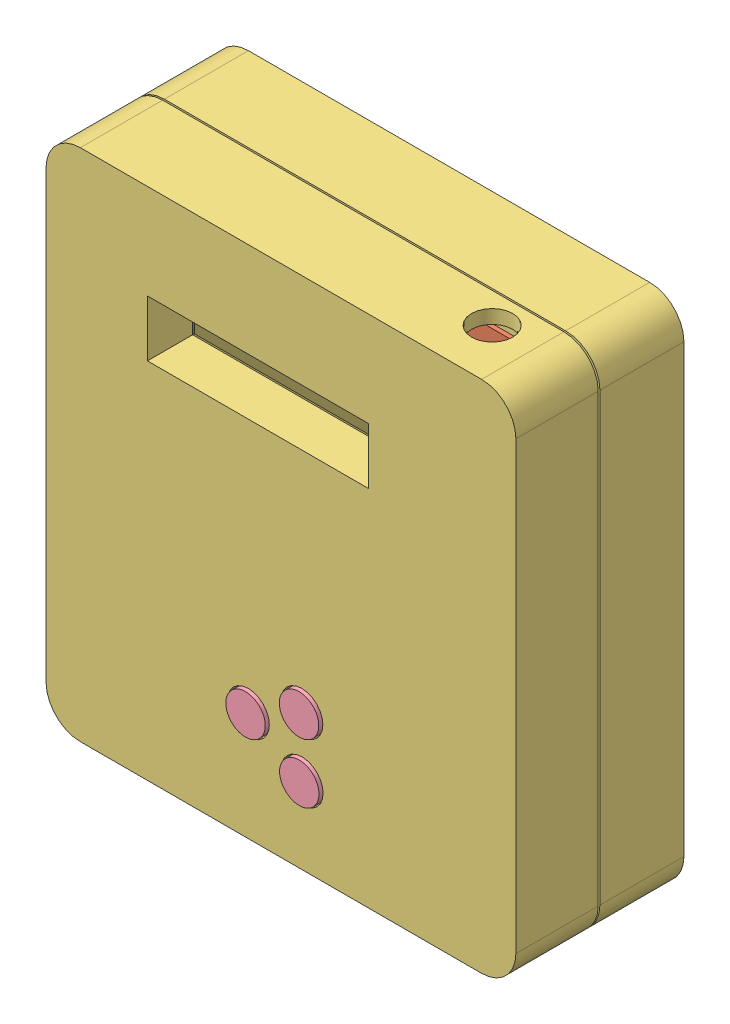
SolidWorks assembly Handheld Terminal, configuration Default. Lengths in mm.
Overall size (137 150 49.83).
106 component instances, 23 part files, 18 mates.
Components (placement in the parent):
- Handheld Terminal Circuit-1: Handheld Terminal Circuit [Default] at origin size (116.81 129.48 28.62)
  - Handheld Terminal Circuit.STEP-1: Handheld Terminal Circuit.STEP [Default] at origin size (116.81 129.48 28.62)
    - X1.STEP-1: X1.STEP [Default] at (-24.8494 -12.1588 0.625) x (0 1 0) z (0 0 1) size (11 4.5 15.2)
      - Open CASCADE STEP translator 6.8 2.2.1.STEP-1: Open CASCADE STEP translator 6.8 2.2.1.STEP [Default] at origin size (11 4.5 15.2)
        - Body_1.STEP-1: Body_1.STEP [Default] at (2.5 0 0) x (1 0 0) z (0 -1 0) size (11 15.2 4.5)
    - J1.STEP-1: J1.STEP [Default] at (27.8456 -53.6484 0.625) x (-1 0 0) z (0 0 1) size (10.16 10.16 8.71)
      - Open CASCADE STEP translator 6.8 2.3.1.STEP-1: Open CASCADE STEP translator 6.8 2.3.1.STEP [Default] at origin size (10.16 10.16 8.71)
        - Body_1-0.STEP-1: Body_1-0.STEP [Default] at origin size (10.16 10.16 3)
        - Pin_1.STEP-1: Pin_1.STEP [Default] x (0 -1 0) z (0 0 1) size (1.42 1.42 7.92)
        - Pin_2.STEP-1: Pin_2.STEP [Default] at (5.08 5.08 0) x (0 -1 0) z (0 0 1) size (1.42 1.42 7.92)
    - U2.STEP-1: U2.STEP [Default] at (37.1858 -34.3162 -0.625) x (0 -1 0) z (0 0 -1) size (3.55 6.6 1.62)
      - Open CASCADE STEP translator 6.8 2.4.1.STEP-1: Open CASCADE STEP translator 6.8 2.4.1.STEP [Default] at origin size (3.55 6.6 1.62)
        - Body_1-1.STEP-1: Body_1-1.STEP [Default] at origin size (3.55 6.6 1.62)
    - R1.STEP-1: R1.STEP [Default] at (-50.4294 44.6446 0.625) x (0 -1 0) z (0 0 1) size (10.82 1.37 5.33)
      - Open CASCADE STEP translator 6.8 2.5.1.STEP-1: Open CASCADE STEP translator 6.8 2.5.1.STEP [Default] at origin size (10.82 1.37 5.33)
        - Body_1-2.STEP-1: Body_1-2.STEP [Default] at origin size (5.08 1.37 1.37)
        - Pin_1-3.STEP-1: Pin_1-3.STEP [Default] at origin size (3.2 0.66 4.98)
        - Pin_2-4.STEP-1: Pin_2-4.STEP [Default] at (20.32 0 0) x (-1 0 0) z (0 0 1) size (3.2 0.66 4.98)
    - R2.STEP-1: R2.STEP [Default] at (-20.066 15.8496 0.625) size (10.82 1.37 5.33)
      - Open CASCADE STEP translator 6.8 2.5.1.STEP-1: Open CASCADE STEP translator 6.8 2.5.1.STEP [Default] at origin size (10.82 1.37 5.33)
        - Body_1-2.STEP-1: Body_1-2.STEP [Default] at origin size (5.08 1.37 1.37)
        - Pin_1-3.STEP-1: Pin_1-3.STEP [Default] at origin size (3.2 0.66 4.98)
        - Pin_2-4.STEP-1: Pin_2-4.STEP [Default] at (20.32 0 0) x (-1 0 0) z (0 0 1) size (3.2 0.66 4.98)
    - R3.STEP-1: R3.STEP [Default] at (-19.1008 -43.1546 0.625) x (-1 0 0) z (0 0 1) size (10.82 1.37 5.33)
      - Open CASCADE STEP translator 6.8 2.5.1.STEP-1: Open CASCADE STEP translator 6.8 2.5.1.STEP [Default] at origin size (10.82 1.37 5.33)
        - Body_1-2.STEP-1: Body_1-2.STEP [Default] at origin size (5.08 1.37 1.37)
        - Pin_1-3.STEP-1: Pin_1-3.STEP [Default] at origin size (3.2 0.66 4.98)
        - Pin_2-4.STEP-1: Pin_2-4.STEP [Default] at (20.32 0 0) x (-1 0 0) z (0 0 1) size (3.2 0.66 4.98)
    - R4.STEP-1: R4.STEP [Default] at (-19.1008 -39.751 0.625) x (-1 0 0) z (0 0 1) size (10.82 1.37 5.33)
      - Open CASCADE STEP translator 6.8 2.5.1.STEP-1: Open CASCADE STEP translator 6.8 2.5.1.STEP [Default] at origin size (10.82 1.37 5.33)
        - Body_1-2.STEP-1: Body_1-2.STEP [Default] at origin size (5.08 1.37 1.37)
        - Pin_1-3.STEP-1: Pin_1-3.STEP [Default] at origin size (3.2 0.66 4.98)
        - Pin_2-4.STEP-1: Pin_2-4.STEP [Default] at (20.32 0 0) x (-1 0 0) z (0 0 1) size (3.2 0.66 4.98)
    - R5.STEP-1: R5.STEP [Default] at (-19.2024 -46.2788 0.625) x (-1 0 0) z (0 0 1) size (10.82 1.37 5.33)
      - Open CASCADE STEP translator 6.8 2.5.1.STEP-1: Open CASCADE STEP translator 6.8 2.5.1.STEP [Default] at origin size (10.82 1.37 5.33)
        - Body_1-2.STEP-1: Body_1-2.STEP [Default] at origin size (5.08 1.37 1.37)
        - Pin_1-3.STEP-1: Pin_1-3.STEP [Default] at origin size (3.2 0.66 4.98)
        - Pin_2-4.STEP-1: Pin_2-4.STEP [Default] at (20.32 0 0) x (-1 0 0) z (0 0 1) size (3.2 0.66 4.98)
    - C1.STEP-1: C1.STEP [Default] at (-36.1294 -7.2788 0.625) size (8 2 13.25)
      - Open CASCADE STEP translator 6.8 2.10.1.STEP-1: Open CASCADE STEP translator 6.8 2.10.1.STEP [Default] at origin size (8 2 13.25)
        - Body_1-5.STEP-1: Body_1-5.STEP [Default] at (2.54 -2.54 0) x (0 1 0) z (0 0 1) size (2 8 8)
        - Pin_1-6.STEP-1: Pin_1-6.STEP [Default] x (0 -1 0) z (0 0 1) size (0.5 0.5 9.5)
        - Pin_2-7.STEP-1: Pin_2-7.STEP [Default] at (5.08 5.08 0) x (0 -1 0) z (0 0 1) size (0.5 0.5 9.5)
    - C2.STEP-1: C2.STEP [Default] at (-36.1494 -11.6788 0.625) size (8 2 13.25)
      - Open CASCADE STEP translator 6.8 2.10.1.STEP-1: Open CASCADE STEP translator 6.8 2.10.1.STEP [Default] at origin size (8 2 13.25)
        - Body_1-5.STEP-1: Body_1-5.STEP [Default] at (2.54 -2.54 0) x (0 1 0) z (0 0 1) size (2 8 8)
        - Pin_1-6.STEP-1: Pin_1-6.STEP [Default] x (0 -1 0) z (0 0 1) size (0.5 0.5 9.5)
        - Pin_2-7.STEP-1: Pin_2-7.STEP [Default] at (5.08 5.08 0) x (0 -1 0) z (0 0 1) size (0.5 0.5 9.5)
    - LCD1.STEP-1: LCD1.STEP [Default] at (-19.686 56.143 0.625) size (80 36 10.2)
      - Open CASCADE STEP translator 6.8 2.12.1.STEP-1: Open CASCADE STEP translator 6.8 2.12.1.STEP [Default] at origin size (80 36 10.2)
        - Body_1-8.STEP-1: Body_1-8.STEP [Default] at (13 -17 0) x (1 0 0) z (0 -1 0) size (80 10.2 36)
    - SW1.STEP-1: SW1.STEP [Default] at (-7.2644 -37.4396 0.625) x (0 -1 0) z (0 0 1) size (12.01 10.01 12.01)
      - Open CASCADE STEP translator 6.8 2.13.1.STEP-1: Open CASCADE STEP translator 6.8 2.13.1.STEP [Default] at origin size (12.01 10.01 12.01)
        - Body_1-9.STEP-1: Body_1-9.STEP [Default] at (6 -2 0) x (1 0 0) z (0 -1 0) size (12.01 10.01 12.01)
    - SW2.STEP-1: SW2.STEP [Default] at (8.3378 -29.1306 0.625) x (0 -1 0) z (0 0 1) size (12.01 10.01 12.01)
      - Open CASCADE STEP translator 6.8 2.14.1.STEP-1: Open CASCADE STEP translator 6.8 2.14.1.STEP [Default] at origin size (12.01 10.01 12.01)
        - Body_1-9.STEP-1: Body_1-9.STEP [Default] at (6 -2 0) x (1 0 0) z (0 -1 0) size (12.01 10.01 12.01)
    - SW3.STEP-1: SW3.STEP [Default] at (8.411 -46.3848 0.625) x (0 -1 0) z (0 0 1) size (12.01 10.01 12.01)
      - Open CASCADE STEP translator 6.8 2.15.1.STEP-1: Open CASCADE STEP translator 6.8 2.15.1.STEP [Default] at origin size (12.01 10.01 12.01)
        - Body_1-9.STEP-1: Body_1-9.STEP [Default] at (6 -2 0) x (1 0 0) z (0 -1 0) size (12.01 10.01 12.01)
    - C5.STEP-1: C5.STEP [Default] at (37.2474 -27.8864 0.625) x (-1 0 0) z (0 0 1) size (8 2 13.25)
      - Open CASCADE STEP translator 6.8 2.10.1.STEP-1: Open CASCADE STEP translator 6.8 2.10.1.STEP [Default] at origin size (8 2 13.25)
        - Body_1-5.STEP-1: Body_1-5.STEP [Default] at (2.54 -2.54 0) x (0 1 0) z (0 0 1) size (2 8 8)
        - Pin_1-6.STEP-1: Pin_1-6.STEP [Default] x (0 -1 0) z (0 0 1) size (0.5 0.5 9.5)
        - Pin_2-7.STEP-1: Pin_2-7.STEP [Default] at (5.08 5.08 0) x (0 -1 0) z (0 0 1) size (0.5 0.5 9.5)
    - C6.STEP-1: C6.STEP [Default] at (36.3584 -21.13 0.625) x (-1 0 0) z (0 0 1) size (5.84 5.84 8.33)
      - Open CASCADE STEP translator 6.8 2.17.1.STEP-1: Open CASCADE STEP translator 6.8 2.17.1.STEP [Default] at origin size (5.84 5.84 8.33)
        - Body_1-10.STEP-1: Body_1-10.STEP [Default] at origin size (5.84 5.84 3)
        - Pin_1-11.STEP-1: Pin_1-11.STEP [Default] x (0 -1 0) z (0 0 1) size (0.66 0.66 7.16)
        - Pin_2-12.STEP-1: Pin_2-12.STEP [Default] at (3.175 3.175 0) x (0 -1 0) z (0 0 1) size (0.66 0.66 7.16)
    - U1.STEP-1: U1.STEP [Default] at (-17.9284 11.5356 0.625) x (0 -1 0) z (0 0 1) size (35.56 7.92 7.75)
      - Open CASCADE STEP translator 6.8 2.18.1.STEP-1: Open CASCADE STEP translator 6.8 2.18.1.STEP [Default] at origin size (35.56 7.92 7.75)
        - Body_1-13.STEP-1: Body_1-13.STEP [Default] at (16.5 3.8 0) x (0 1 0) z (1 0 0) size (7.92 7.75 35.56)
    - U3.STEP-1: U3.STEP [Default] at (25.5126 -34.084 0.625) size (9.97 4.45 28.62)
      - Open CASCADE STEP translator 6.8 2.19.1.STEP-1: Open CASCADE STEP translator 6.8 2.19.1.STEP [Default] at origin size (9.97 4.45 28.62)
        - Body_1-14.STEP-1: Body_1-14.STEP [Default] at (0 3 3.5) x (1 0 0) z (0 -1 0) size (9.97 28.62 4.45)
    - C7.STEP-1: C7.STEP [Default] at (23.252 -43.9138 0.625) size (5.84 5.84 8.33)
      - Open CASCADE STEP translator 6.8 2.17.1.STEP-1: Open CASCADE STEP translator 6.8 2.17.1.STEP [Default] at origin size (5.84 5.84 8.33)
        - Body_1-10.STEP-1: Body_1-10.STEP [Default] at origin size (5.84 5.84 3)
        - Pin_1-11.STEP-1: Pin_1-11.STEP [Default] x (0 -1 0) z (0 0 1) size (0.66 0.66 7.16)
        - Pin_2-12.STEP-1: Pin_2-12.STEP [Default] at (3.175 3.175 0) x (0 -1 0) z (0 0 1) size (0.66 0.66 7.16)
    - C8.STEP-1: C8.STEP [Default] at (22.1344 -37.8178 0.625) size (8 2 13.25)
      - Open CASCADE STEP translator 6.8 2.10.1.STEP-1: Open CASCADE STEP translator 6.8 2.10.1.STEP [Default] at origin size (8 2 13.25)
        - Body_1-5.STEP-1: Body_1-5.STEP [Default] at (2.54 -2.54 0) x (0 1 0) z (0 0 1) size (2 8 8)
        - Pin_1-6.STEP-1: Pin_1-6.STEP [Default] x (0 -1 0) z (0 0 1) size (0.5 0.5 9.5)
        - Pin_2-7.STEP-1: Pin_2-7.STEP [Default] at (5.08 5.08 0) x (0 -1 0) z (0 0 1) size (0.5 0.5 9.5)
    - C9.STEP-1: C9.STEP [Default] at (26.7572 -25.067 0.625) x (-1 0 0) z (0 0 1) size (5.84 5.84 8.33)
      - Open CASCADE STEP translator 6.8 2.17.1.STEP-1: Open CASCADE STEP translator 6.8 2.17.1.STEP [Default] at origin size (5.84 5.84 8.33)
        - Body_1-10.STEP-1: Body_1-10.STEP [Default] at origin size (5.84 5.84 3)
        - Pin_1-11.STEP-1: Pin_1-11.STEP [Default] x (0 -1 0) z (0 0 1) size (0.66 0.66 7.16)
        - Pin_2-12.STEP-1: Pin_2-12.STEP [Default] at (3.175 3.175 0) x (0 -1 0) z (0 0 1) size (0.66 0.66 7.16)
    - C10.STEP-1: C10.STEP [Default] at (27.7732 -18.7424 0.625) x (-1 0 0) z (0 0 1) size (8 2 13.25)
      - Open CASCADE STEP translator 6.8 2.10.1.STEP-1: Open CASCADE STEP translator 6.8 2.10.1.STEP [Default] at origin size (8 2 13.25)
        - Body_1-5.STEP-1: Body_1-5.STEP [Default] at (2.54 -2.54 0) x (0 1 0) z (0 0 1) size (2 8 8)
        - Pin_1-6.STEP-1: Pin_1-6.STEP [Default] x (0 -1 0) z (0 0 1) size (0.5 0.5 9.5)
        - Pin_2-7.STEP-1: Pin_2-7.STEP [Default] at (5.08 5.08 0) x (0 -1 0) z (0 0 1) size (0.5 0.5 9.5)
    - RF24.STEP-1: RF24.STEP [Default] at (46.3962 10.2222 0.625) size (16 49 14.37)
      - Open CASCADE STEP translator 6.8 2.24.1.STEP-1: Open CASCADE STEP translator 6.8 2.24.1.STEP [Default] at origin size (16 49 14.37)
        - Body_1-15.STEP-1: Body_1-15.STEP [Default] x (1 0 0) z (0 -1 0) size (16 14.37 49)
    - Layer_1.STEP-1: Layer_1.STEP [Default] at origin size (116.81 129.48 1.25)
- Handheld Terminal Casing-1: Handheld Terminal Casing [Default] at origin size (137 150 49)
- Button13mm-2: Button13mm [Default] at (-9.5144 -43.1896 6.425) x (-1 0 0) z (0 0 -1) size (12.8 12.8 21.6)
- Button13mm-3: Button13mm [Default] at (6.161 -52.6348 6.425) x (-1 0 0) z (0 0 -1) size (12.8 12.8 21.6)
- Button13mm-4: Button13mm [Default] at (6.0878 -35.3806 6.425) x (-1 0 0) z (0 0 -1) size (12.8 12.8 21.6)
- Lipo18650-1: Lipo18650 [Default] at (-8.8995 -69 -11.75) x (0.976994 0 -0.213265) z (0.213265 0 0.976994) size (18.5 65 18.5)
- Lipo18650-2: Lipo18650 [Default] at (9.6005 -69 -11.75) x (0.996077 0 0.088495) z (-0.088495 0 0.996077) size (18.5 65 18.5)
Mates (geometry in assembly coordinates):
- InPlace1: in place: plane of ? through (0 0 0) normal (0 0 1); moOrthogonalPlaneRef_w of ? through (0 0 0) normal (0 1 0); plane of ? through (0 0 0) normal (1 0 0); unknown of ?
- Coincident1: coincident: plane of assembly; plane of Handheld Terminal Casing-1; plane of assembly
- Coincident2: coincident: plane of ? through (0 0 0) normal (0 1 0)
- Coincident3: coincident: plane of ? through (0 0 0) normal (1 0 0)
- Distance3: distance = 0.5 mm: plane of assembly; plane of assembly; plane of Button13mm-2 through (-8.5144 -45.9396 25.8189) normal (0 -1 0); plane of Handheld Terminal Circuit-1/Handheld Terminal Circuit.STEP-1/SW1.STEP-1/Open CASCADE STEP translator 6.8 2.13.1.STEP-1/Body_1-9.STEP-1 through (-11.2644 -45.4396 7.125) normal (0 -1 0)
- Distance4: distance = 0.5 mm: plane of assembly; plane of assembly; plane of Button13mm-2 through (-6.7644 -41.2896 25.8189) normal (1 0 0); plane of Handheld Terminal Circuit-1/Handheld Terminal Circuit.STEP-1/SW1.STEP-1/Open CASCADE STEP translator 6.8 2.13.1.STEP-1/Body_1-9.STEP-1 through (-7.2644 -45.4396 7.125) normal (1 0 0)
- Distance5: distance = 1 mm: plane of assembly; plane of assembly; plane of Button13mm-2 through (-9.5144 -43.1896 5.125) normal (0 0 -1); plane of Handheld Terminal Circuit-1/Handheld Terminal Circuit.STEP-1/SW1.STEP-1/Open CASCADE STEP translator 6.8 2.13.1.STEP-1/Body_1-9.STEP-1 through (-9.2644 -43.4396 4.125) normal (0 0 1)
- Distance6: distance = 0.5 mm: plane of Button13mm-3 through (8.911 -50.7348 25.8189) normal (1 0 0); plane of Handheld Terminal Circuit-1/Handheld Terminal Circuit.STEP-1/SW3.STEP-1/Open CASCADE STEP translator 6.8 2.15.1.STEP-1/Body_1-9.STEP-1 through (8.411 -54.3848 7.125) normal (1 0 0)
- Distance7: distance = 0.5 mm: plane of Button13mm-3 through (7.161 -49.8848 25.8189) normal (0 1 0); plane of Handheld Terminal Circuit-1/Handheld Terminal Circuit.STEP-1/SW3.STEP-1/Open CASCADE STEP translator 6.8 2.15.1.STEP-1/Body_1-9.STEP-1 through (4.411 -50.3848 7.125) normal (0 1 0)
- Distance8: distance = 1 mm: plane of Button13mm-3 through (6.161 -52.6348 5.125) normal (0 0 -1); plane of Handheld Terminal Circuit-1/Handheld Terminal Circuit.STEP-1/SW3.STEP-1/Open CASCADE STEP translator 6.8 2.15.1.STEP-1/Body_1-9.STEP-1 through (6.411 -52.3848 4.125) normal (0 0 1)
- Distance9: distance = 0.5 mm: plane of Button13mm-4 through (8.8378 -33.4806 25.8189) normal (1 0 0); plane of Handheld Terminal Circuit-1/Handheld Terminal Circuit.STEP-1/SW2.STEP-1/Open CASCADE STEP translator 6.8 2.14.1.STEP-1/Body_1-9.STEP-1 through (8.3378 -37.1306 7.125) normal (1 0 0)
- Distance10: distance = 0.5 mm: plane of Button13mm-4 through (7.0878 -32.6306 25.8189) normal (0 1 0); plane of Handheld Terminal Circuit-1/Handheld Terminal Circuit.STEP-1/SW2.STEP-1/Open CASCADE STEP translator 6.8 2.14.1.STEP-1/Body_1-9.STEP-1 through (4.3378 -33.1306 7.125) normal (0 1 0)
- Distance11: distance = 1 mm: plane of Button13mm-4 through (6.0878 -35.3806 5.125) normal (0 0 -1); plane of Handheld Terminal Circuit-1/Handheld Terminal Circuit.STEP-1/SW2.STEP-1/Open CASCADE STEP translator 6.8 2.14.1.STEP-1/Body_1-9.STEP-1 through (6.3378 -35.1306 4.125) normal (0 0 1)
- Coincident9: coincident: plane of assembly; plane of assembly; plane of Lipo18650-1 through (-8.8995 -69 -11.75) normal (0 -1 0); plane of Lipo18650-2 through (9.6005 -69 -11.75) normal (0 -1 0)
- Tangent1: tangent: cylinder of assembly; cylinder of assembly; cylinder of Lipo18650-1 through (-8.8995 -4 -11.75) axis (0 -1 0) radius 9.25; cylinder of Lipo18650-2 through (9.6005 -4 -11.75) axis (0 -1 0) radius 9.25
- Tangent2: tangent: plane of ? through (-58.5 -65 -21) normal (0 0 1); cylinder of Lipo18650-2 through (9.6005 -4 -11.75) axis (0 -1 0) radius 9.25
- Tangent3: tangent: plane of ? through (-58.5 -65 -21) normal (0 0 1); cylinder of Lipo18650-1 through (-8.8995 -4 -11.75) axis (0 -1 0) radius 9.25
- Distance12: distance = 2 mm: plane of ? through (58.5 -71 -25) normal (0 1 0); plane of Lipo18650-1 through (-8.8995 -69 -11.75) normal (0 -1 0)
